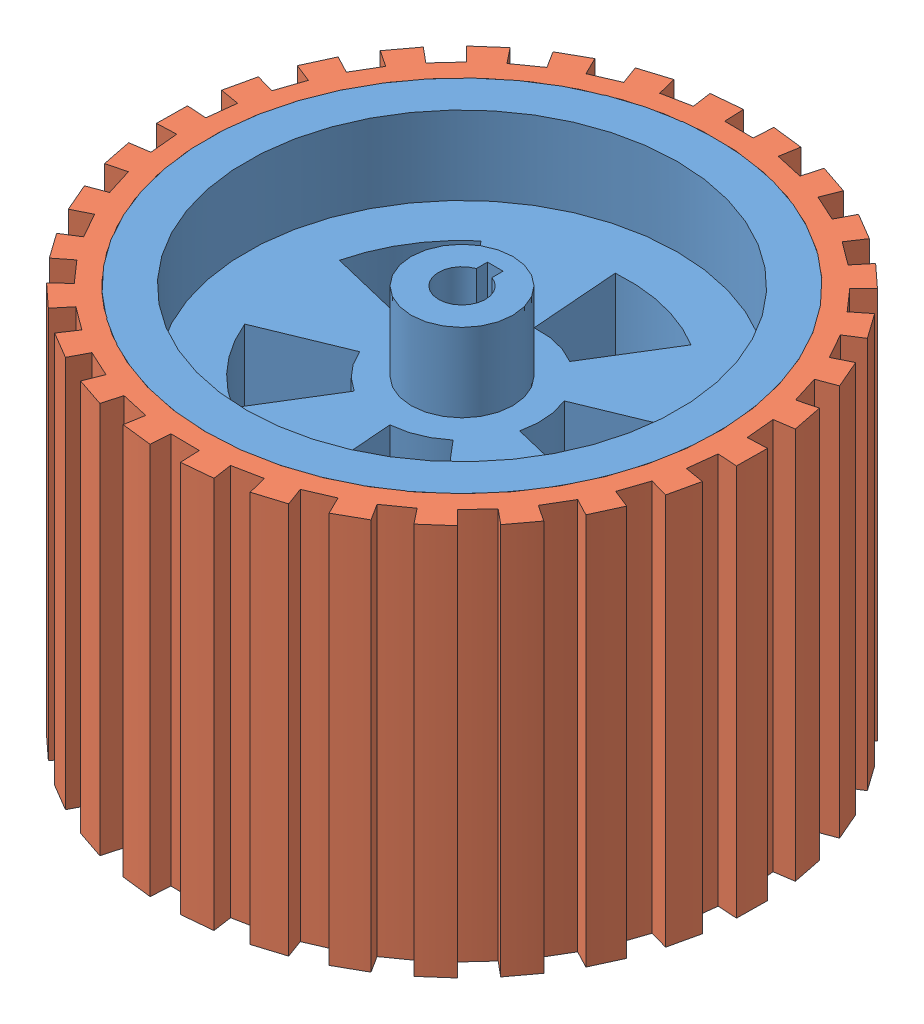
SolidWorks assembly side wheel (rubber+rim), configuration Default. Lengths in mm.
Overall size (211.82 100 211.83).
2 component instances, 2 part files, 2 mates.
Components (placement in the parent):
- side wheel rim-1: side wheel rim [Default] at (68.1365 40.0161 108.3416) size (130 100 130)
- side wheel rubber-1: side wheel rubber [Default] at (68.1365 40.0161 108.3416) x (0.734903 0 0.678172) z (-0.678172 0 0.734903) size (149.8 100 150)
Mates (geometry in assembly coordinates):
- Coincident1: coincident aligned: circle of side wheel rim-1; circle of side wheel rubber-1
- Lock1: lock: unknown of side wheel rim-1; unknown of side wheel rubber-1
